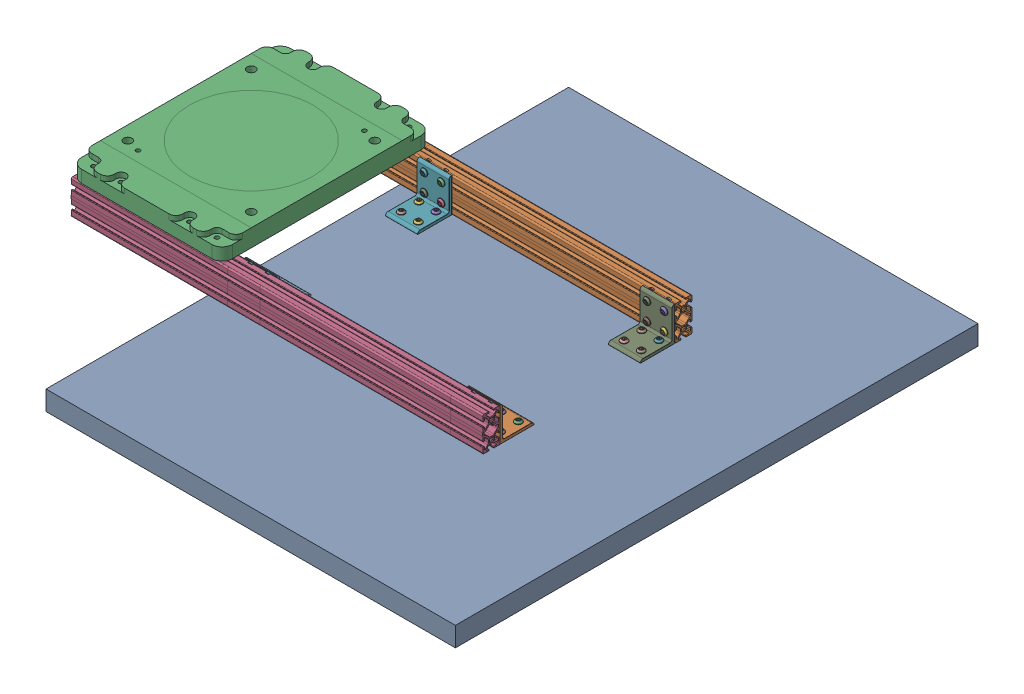
SolidWorks assembly Geometry_Export_Main_Layout_Assembly, configuration Default. Lengths in mm.
Overall size (795.9 103.45 762).
54 component instances, 13 part files, 10 mates.
Components (placement in the parent):
- Optic_Table_simplified-1: Optic_Table_simplified [Default] at (291.6121 412.7969 753.2128) size (596.9 28.5 762)
- Simplified_Mount_Frame_IRB1200-1: Simplified_Mount_Frame_IRB1200 [Default] at (908.2296 -379.1035 -73.0699) x (0 0 1) z (-1 0 0) size (305.01 75.17 600)
  - 2550_L320T-slot_6575N411-1: 2550_L320T-slot_6575N411 [6575N411] at (666.2827 845.1753 1112.5175) size (25.01 50 600)
  - Grundplatte Typ L - H35mm_V03-1: Grundplatte Typ L - H35mm_V03 [Default] at (806.2827 869.9502 1302.5175) x (1 0 0) z (0 1 0) size (304.8 220 25.4)
  - 2550_L320T-slot_6575N411-2: 2550_L320T-slot_6575N411 [6575N411] at (946.2827 845.1753 1112.5175) size (25.01 50 600)
  - Assem_4844N114_T-Slotted Framing Structural Bracket^Simplified_Mount_Frame_IRB1200-1: Assem_4844N114_T-Slotted Framing Structural Bracket^Simplified_Mount_Frame_IRB1200 [Default] at (680.7827 822.4005 836.0175) x (0 0 -1) z (1 0 0) size (47 49.99 49.99) (virtual)
    - 4844N114_T-Slotted Framing Structural Bracket-1: 4844N114_T-Slotted Framing Structural Bracket [4844N114] at origin size (47 56.94 56.94)
    - 4976N41_T-Slotted Framing Fasteners-1: 4976N41_T-Slotted Framing Fasteners [4976N41] at (0 35.5 -4.97) (suppressed, hidden)
    - 4976N41_T-Slotted Framing Fasteners-2: 4976N41_T-Slotted Framing Fasteners [4976N41] at (0 10.5 -4.97) (suppressed, hidden)
  - Assem_4844N114_T-Slotted Framing Structural Bracket^Simplified_Mount_Frame_IRB1200-2: Assem_4844N114_T-Slotted Framing Structural Bracket^Simplified_Mount_Frame_IRB1200 [Default] at (931.7827 822.4005 836.0175) x (0 0 1) z (-1 0 0) size (47 49.99 49.99) (virtual)
    - 4844N114_T-Slotted Framing Structural Bracket-1: 4844N114_T-Slotted Framing Structural Bracket [4844N114] at origin size (47 56.94 56.94)
    - 4976N41_T-Slotted Framing Fasteners-1: 4976N41_T-Slotted Framing Fasteners [4976N41] at (0 35.5 -4.97) (suppressed, hidden)
    - 4976N41_T-Slotted Framing Fasteners-2: 4976N41_T-Slotted Framing Fasteners [4976N41] at (0 10.5 -4.97) (suppressed, hidden)
  - Assem_4844N114_T-Slotted Framing Structural Bracket^Simplified_Mount_Frame_IRB1200-3: Assem_4844N114_T-Slotted Framing Structural Bracket^Simplified_Mount_Frame_IRB1200 [Default] at (680.7827 822.4005 1161.0175) x (0 0 -1) z (1 0 0) size (47 49.99 49.99) (virtual)
    - 4844N114_T-Slotted Framing Structural Bracket-1: 4844N114_T-Slotted Framing Structural Bracket [4844N114] at origin size (47 56.94 56.94)
    - 4976N41_T-Slotted Framing Fasteners-1: 4976N41_T-Slotted Framing Fasteners [4976N41] at (0 35.5 -4.97) (suppressed, hidden)
    - 4976N41_T-Slotted Framing Fasteners-2: 4976N41_T-Slotted Framing Fasteners [4976N41] at (0 10.5 -4.97) (suppressed, hidden)
  - Assem_4844N114_T-Slotted Framing Structural Bracket^Simplified_Mount_Frame_IRB1200-4: Assem_4844N114_T-Slotted Framing Structural Bracket^Simplified_Mount_Frame_IRB1200 [Default] at (931.7827 822.4005 1161.0175) x (0 0 1) z (-1 0 0) size (47 49.99 49.99) (virtual)
    - 4844N114_T-Slotted Framing Structural Bracket-1: 4844N114_T-Slotted Framing Structural Bracket [4844N114] at origin size (47 56.94 56.94)
    - 4976N41_T-Slotted Framing Fasteners-1: 4976N41_T-Slotted Framing Fasteners [4976N41] at (0 35.5 -4.97) (suppressed, hidden)
    - 4976N41_T-Slotted Framing Fasteners-2: 4976N41_T-Slotted Framing Fasteners [4976N41] at (0 10.5 -4.97) (suppressed, hidden)
  - M6_L25^Simplified_Mount_Frame_IRB1200-1: M6_L25^Simplified_Mount_Frame_IRB1200 [Default] at (946.2827 865.7002 1392.5175) x (0 0 -1) z (0 1 0) (suppressed, hidden, virtual)
  - M6_L25^Simplified_Mount_Frame_IRB1200-2: M6_L25^Simplified_Mount_Frame_IRB1200 [Default] at (946.2827 865.7002 1352.5175) x (0 0 -1) z (0 1 0) (suppressed, hidden, virtual)
  - M6_L25^Simplified_Mount_Frame_IRB1200-3: M6_L25^Simplified_Mount_Frame_IRB1200 [Default] at (946.2827 865.7002 1252.5175) x (0 0 -1) z (0 1 0) (suppressed, hidden, virtual)
  - M6_L25^Simplified_Mount_Frame_IRB1200-4: M6_L25^Simplified_Mount_Frame_IRB1200 [Default] at (946.2827 865.7002 1212.5175) x (0 0 -1) z (0 1 0) (suppressed, hidden, virtual)
  - M6_L25^Simplified_Mount_Frame_IRB1200-5: M6_L25^Simplified_Mount_Frame_IRB1200 [Default] at (666.2827 865.7002 1392.5175) x (0 0 -1) z (0 1 0) (suppressed, hidden, virtual)
  - M6_L25^Simplified_Mount_Frame_IRB1200-6: M6_L25^Simplified_Mount_Frame_IRB1200 [Default] at (666.2827 865.7002 1352.5175) x (0 0 -1) z (0 1 0) (suppressed, hidden, virtual)
  - M6_L25^Simplified_Mount_Frame_IRB1200-7: M6_L25^Simplified_Mount_Frame_IRB1200 [Default] at (666.2827 865.7002 1252.5175) x (0 0 -1) z (0 1 0) (suppressed, hidden, virtual)
  - M6_L25^Simplified_Mount_Frame_IRB1200-8: M6_L25^Simplified_Mount_Frame_IRB1200 [Default] at (666.2827 865.7002 1212.5175) x (0 0 -1) z (0 1 0) (suppressed, hidden, virtual)
  - 91595A452_Dowel Pin-1: 91595A452_Dowel Pin [91595A452] at (711.2827 894.4502 1232.5175) x (-0.059436 0 -0.998232) z (0 1 0) (suppressed, hidden)
  - 91595A452_Dowel Pin-2: 91595A452_Dowel Pin [91595A452] at (901.2827 894.4502 1372.5175) x (0.75564 0 0.654988) z (0 1 0) (suppressed, hidden)
  - M12_L70^Simplified_Mount_Frame_IRB1200-1: M12_L70^Simplified_Mount_Frame_IRB1200 [Default] at (896.2827 879.5207 1392.5175) x (1 0 0) z (0 1 0) (suppressed, hidden, virtual)
  - M12_L70^Simplified_Mount_Frame_IRB1200-2: M12_L70^Simplified_Mount_Frame_IRB1200 [Default] at (896.2827 879.5207 1212.5175) x (1 0 0) z (0 1 0) (suppressed, hidden, virtual)
  - M12_L70^Simplified_Mount_Frame_IRB1200-3: M12_L70^Simplified_Mount_Frame_IRB1200 [Default] at (716.2827 879.5207 1212.5175) x (1 0 0) z (0 1 0) (suppressed, hidden, virtual)
  - M12_L70^Simplified_Mount_Frame_IRB1200-4: M12_L70^Simplified_Mount_Frame_IRB1200 [Default] at (716.2827 879.5207 1392.5175) x (1 0 0) z (0 1 0) (suppressed, hidden, virtual)
- IRB1200H_5-90_IRC5__Standard_rev0-1: IRB1200H_5-90_IRC5__Standard_rev0 [Default] at (-394.2879 516.2467 733.2128) x (1 0 0) z (0 1 0) size (735.68 269.27 977.6) (suppressed, hidden)
  - IRB1200H_5-90_IRC5__Standard_rev0.step-1: IRB1200H_5-90_IRC5__Standard_rev0.step [Default] at origin size (735.68 269.27 977.6)
    - IRB1200H_5-90_IRC5__Standard_rev0_1.step-1: IRB1200H_5-90_IRC5__Standard_rev0_1.step [Default] at origin size (311.72 239.08 234)
    - IRB1200H_5-90_IRC5__Standard_rev0_2.step-1: IRB1200H_5-90_IRC5__Standard_rev0_2.step [Default] at origin size (277.55 121.5 164.94)
    - IRB1200H_5-90_IRC5__Standard_rev0_3.step-1: IRB1200H_5-90_IRC5__Standard_rev0_3.step [Default] at origin size (159.7 235.02 598.06)
    - IRB1200H_5-90_IRC5__Standard_rev0_4.step-1: IRB1200H_5-90_IRC5__Standard_rev0_4.step [Default] at origin size (264.86 269.27 262.4)
    - IRB1200H_5-90_IRC5__Standard_rev0_5.step-1: IRB1200H_5-90_IRC5__Standard_rev0_5.step [Default] at origin size (369.7 147.71 193)
    - IRB1200H_5-90_IRC5__Standard_rev0_6.step-1: IRB1200H_5-90_IRC5__Standard_rev0_6.step [Default] at origin size (5.5 44 43.99)
    - IRB1200H_5-90_IRC5__Standard_rev0_7.step-1: IRB1200H_5-90_IRC5__Standard_rev0_7.step [Default] at origin size (146.45 107 95)
- Mount_Frame_IRB1200-2: Mount_Frame_IRB1200 [Default] at (-325.0054 -379.1035 1539.4955) x (0 0 -1) z (1 0 0) (suppressed, hidden)
- IRB1200H_5-90_IRC5__Standard_rev0-2: IRB1200H_5-90_IRC5__Standard_rev0 [Default] at (977.5121 516.2467 733.2128) x (-1 0 0) z (0 1 0) size (735.68 269.27 977.6) (suppressed, hidden)
  - IRB1200H_5-90_IRC5__Standard_rev0.step-1: IRB1200H_5-90_IRC5__Standard_rev0.step [Default] at origin size (735.68 269.27 977.6)
    - IRB1200H_5-90_IRC5__Standard_rev0_1.step-1: IRB1200H_5-90_IRC5__Standard_rev0_1.step [Default] at origin size (311.72 239.08 234)
    - IRB1200H_5-90_IRC5__Standard_rev0_2.step-1: IRB1200H_5-90_IRC5__Standard_rev0_2.step [Default] at origin size (277.55 121.5 164.94)
    - IRB1200H_5-90_IRC5__Standard_rev0_3.step-1: IRB1200H_5-90_IRC5__Standard_rev0_3.step [Default] at origin size (159.7 235.02 598.06)
    - IRB1200H_5-90_IRC5__Standard_rev0_4.step-1: IRB1200H_5-90_IRC5__Standard_rev0_4.step [Default] at origin size (264.86 269.27 262.4)
    - IRB1200H_5-90_IRC5__Standard_rev0_5.step-1: IRB1200H_5-90_IRC5__Standard_rev0_5.step [Default] at origin size (369.7 147.71 193)
    - IRB1200H_5-90_IRC5__Standard_rev0_6.step-1: IRB1200H_5-90_IRC5__Standard_rev0_6.step [Default] at origin size (5.5 44 43.99)
    - IRB1200H_5-90_IRC5__Standard_rev0_7.step-1: IRB1200H_5-90_IRC5__Standard_rev0_7.step [Default] at origin size (146.45 107 95)
Mates (geometry in assembly coordinates):
- Coincident1: coincident anti-aligned: plane of Mount_Frame_IRB1200-1/Grundplatte Typ L - H35mm_V03-1 through (-404.2879 516.2467 753.2128) normal (0 1 0); plane of IRB1200H_5-90_IRC5__Standard_rev0-1/IRB1200H_5-90_IRC5__Standard_rev0.step-1/IRB1200H_5-90_IRC5__Standard_rev0_1.step-1 through (-394.2879 516.2467 733.2128) normal (0 -1 0)
- Concentric1: concentric aligned: cylinder of Simplified_Mount_Frame_IRB1200-1/Grundplatte Typ L - H35mm_V03-1 through (-304.2879 490.8467 643.2128) axis (0 -1 0) radius 6.1; cylinder of IRB1200H_5-90_IRC5__Standard_rev0-1/IRB1200H_5-90_IRC5__Standard_rev0.step-1/IRB1200H_5-90_IRC5__Standard_rev0_1.step-1 through (-304.2879 516.2467 643.2128) axis (0 -1 0) radius 6.75
- Concentric2: concentric aligned: cylinder of Simplified_Mount_Frame_IRB1200-1/Grundplatte Typ L - H35mm_V03-1 through (-484.2879 490.8467 823.2128) axis (0 -1 0) radius 6.1; cylinder of IRB1200H_5-90_IRC5__Standard_rev0-1/IRB1200H_5-90_IRC5__Standard_rev0.step-1/IRB1200H_5-90_IRC5__Standard_rev0_1.step-1 through (-484.2879 516.2467 823.2128) axis (0 -1 0) radius 6.75
- Coincident2: coincident anti-aligned: plane of Optic_Table_simplified-1 through (291.6121 441.2969 753.2128) normal (0 1 0); plane of Simplified_Mount_Frame_IRB1200-1/Assem_4844N114_T-Slotted Framing Structural Bracket^Simplified_Mount_Frame_IRB1200-1/4844N114_T-Slotted Framing Structural Bracket-1 through (48.7121 441.2969 605.7128) normal (0 -1 0)
- Concentric3: concentric anti-aligned: cylinder of Optic_Table_simplified-1 through (84.7121 404.0288 643.2128) axis (0 1 0) radius 3.1; cylinder of Mount_Frame_IRB1200-1/Assem_4844N114_T-Slotted Framing Structural Bracket^Mount_Frame_IRB1200-1/93070A156_Alloy Steel Low-Profile Socket Head Screw-3 through (84.7121 445.2969 643.2128) axis (0 -1 0) radius 5
- Concentric4: concentric anti-aligned: cylinder of Optic_Table_simplified-1 through (84.7121 404.0288 848.2128) axis (0 1 0) radius 3.1; cylinder of Mount_Frame_IRB1200-1/Assem_4844N114_T-Slotted Framing Structural Bracket^Mount_Frame_IRB1200-2/93070A156_Alloy Steel Low-Profile Socket Head Screw-1 through (84.7121 445.2969 848.2128) axis (0 -1 0) radius 5
- Coincident3: coincident anti-aligned: plane of Optic_Table_simplified-1 through (291.6121 441.2969 753.2128) normal (0 1 0); plane of Mount_Frame_IRB1200-2/Assem_4844N114_T-Slotted Framing Structural Bracket^Mount_Frame_IRB1200-2/4844N114_T-Slotted Framing Structural Bracket-1 through (487.5121 441.2969 605.7128) normal (0 -1 0)
- Coincident4: coincident anti-aligned: plane of Mount_Frame_IRB1200-2/Grundplatte Typ L - H35mm_V03-1 through (987.5121 516.2467 713.2128) normal (0 1 0); plane of IRB1200H_5-90_IRC5__Standard_rev0-2/IRB1200H_5-90_IRC5__Standard_rev0.step-1/IRB1200H_5-90_IRC5__Standard_rev0_1.step-1 through (977.5121 516.2467 733.2128) normal (0 -1 0)
- Concentric7: concentric aligned: cylinder of Mount_Frame_IRB1200-2/M12_L70^Mount_Frame_IRB1200-3/90854A823_Zinc Yellow-Chromate Plated Steel Hex Head Screw-1 through (887.5121 464.4467 823.2128) axis (0 -1 0) radius 6; cylinder of IRB1200H_5-90_IRC5__Standard_rev0-2/IRB1200H_5-90_IRC5__Standard_rev0.step-1/IRB1200H_5-90_IRC5__Standard_rev0_1.step-1 through (887.5121 516.2467 823.2128) axis (0 -1 0) radius 6.75
- Concentric8: concentric anti-aligned: cylinder of Mount_Frame_IRB1200-2/91595A452_Dowel Pin-2 through (1047.5121 525.3467 638.2128) axis (0 1 0) radius 3; cylinder of IRB1200H_5-90_IRC5__Standard_rev0-2/IRB1200H_5-90_IRC5__Standard_rev0.step-1/IRB1200H_5-90_IRC5__Standard_rev0_1.step-1 through (1047.5121 516.2467 638.2128) axis (0 -1 0) radius 3.05
